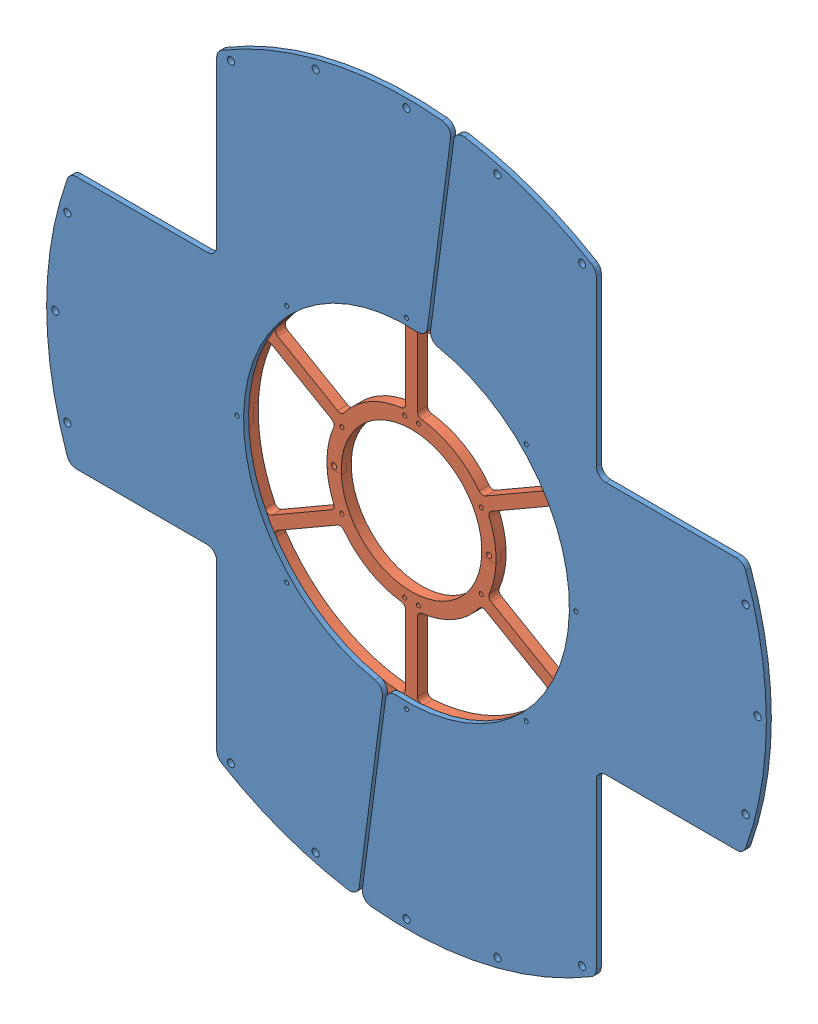
SolidWorks assembly MSC BP Support Plate, configuration Temporary support. Lengths in mm.
Overall size (455 455 9.52).
4 component instances, 2 part files, 9 mates.
Components (placement in the parent):
- MSC BP Temp Support Plate-1: MSC BP Temp Support Plate [Default] at origin size (255.46 452.08 3.17)
- IDS WSC West Beampipe Support-3: IDS WSC West Beampipe Support [Default] at (0 0 -3.175) size (222 116.81 6.35)
- IDS WSC West Beampipe Support-4: IDS WSC West Beampipe Support [Default] at (0 0 -3.175) x (1 0 0) z (0 0 -1) size (222 116.81 6.35)
- MSC BP Temp Support Plate-2: MSC BP Temp Support Plate [Default] x (-1 0 0) z (0 0 1) size (255.46 452.08 3.17)
Mates (geometry in assembly coordinates):
- Coincident1: coincident aligned: plane of MSC BP Temp Support Plate-1 through (0 0 0) normal (0 1 0); plane of assembly through (0 0 0) normal (0 1 0)
- Coincident2: coincident aligned: plane of MSC BP Temp Support Plate-1 through (0 0 0) normal (1 0 0); plane of assembly through (0 0 0) normal (1 0 0)
- Coincident3: coincident aligned: plane of MSC BP Temp Support Plate-1 through (0 0 0) normal (0 0 1); plane of assembly through (0 0 0) normal (0 0 1)
- Coincident5: coincident aligned: plane of IDS WSC West Beampipe Support-3 through (0 0 -3.175) normal (0 1 0); plane of assembly through (0 0 0) normal (0 1 0)
- Coincident6: coincident anti-aligned: plane of IDS WSC West Beampipe Support-4 through (0 0 -3.175) normal (0 -1 0); plane of assembly through (0 0 0) normal (0 1 0)
- Coincident7: coincident aligned: plane of IDS WSC West Beampipe Support-3 through (0 0 -3.175) normal (1 0 0); plane of assembly through (0 0 0) normal (1 0 0)
- Coincident8: coincident aligned: plane of IDS WSC West Beampipe Support-4; plane of assembly through (0 0 0) normal (1 0 0)
- Coincident9: coincident aligned: plane of IDS WSC West Beampipe Support-3 through (0 -244.3414 -6.35) normal (0 0 -1); plane of IDS WSC West Beampipe Support-4 through (0 244.3414 -6.35) normal (0 0 -1)
- Coincident10: coincident anti-aligned: plane of MSC BP Temp Support Plate-1 through (0 0 0) normal (0 0 -1); plane of IDS WSC West Beampipe Support-4 through (0 244.3414 0) normal (0 0 1)
